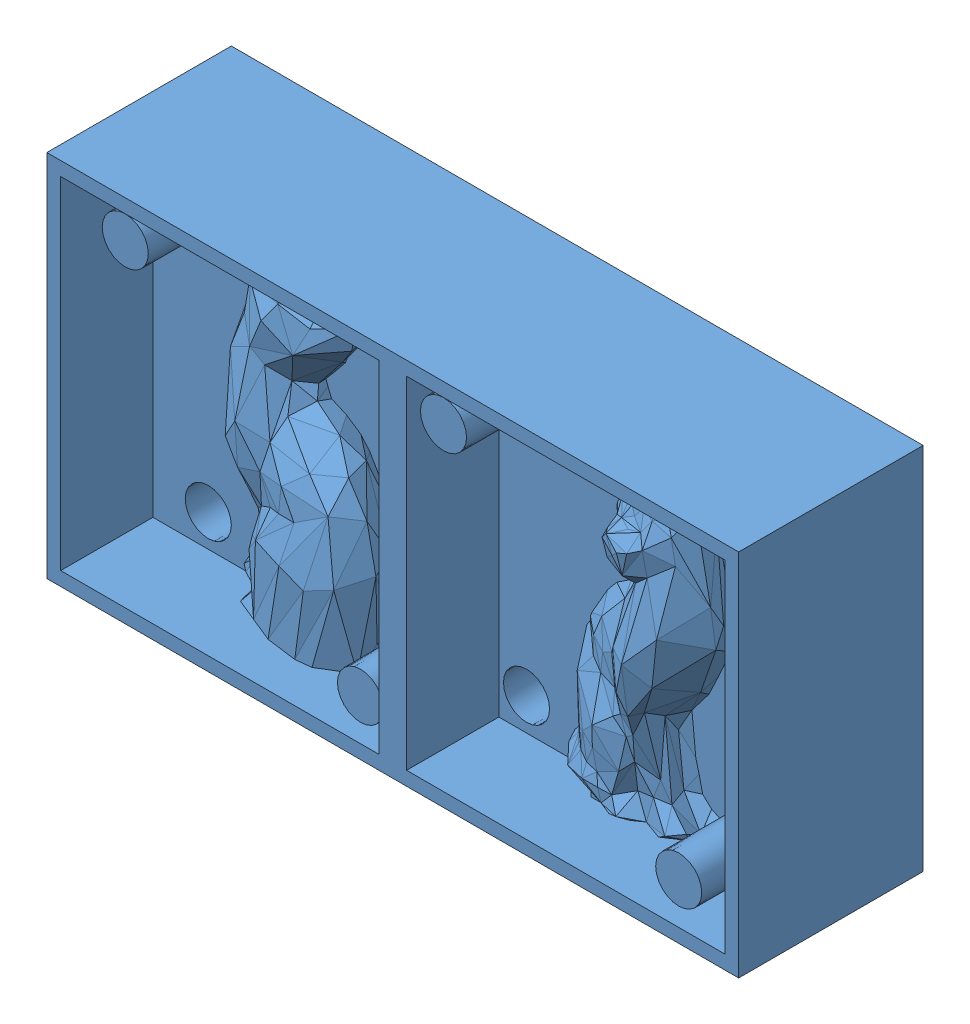
SolidWorks assembly EnsamblajeCat, configuration Predeterminado. Lengths in mm.
Overall size (150 80 40).
3 component instances, 3 part files, 9 mates.
Components (placement in the parent):
- cera-1: cera [Predeterminado] at (3.3673 3.7415 150.05) x (1 0 0) z (0 1 0) size (150 40 80)
- cat back-2: cat back [Predeterminado] at (-33.6496 1.8294 157.829) x (0 0 -1) z (0 1 0) size (14.32 36.7 67.02) (hidden)
- cat front-2: cat front [Predeterminado] at (40.325 -0.9923 158.3372) x (0 0 1) z (0 1 0) size (12.32 35.75 70) (hidden)
Mates (geometry in assembly coordinates):
- Distancia3: distance = 37.5 mm: line of cat front-2 through (40.8673 -30.2585 160.05) axis (0 1 0); line of cera-1 through (78.3673 43.7415 160.05) axis (0 -1 0)
- Distancia5: distance = 37.5 mm: point of assembly; point of cat back-2; moEndPointRef_w of cera-1
- Coincidente13: coincident anti-aligned: plane of cera-1 through (3.3673 3.7415 160.05) normal (0 0 1); plane of cat front-2 through (41.0391 -0.7867 160.05) normal (0 0 -1)
- Coincidente14: coincident anti-aligned: plane of cera-1 through (3.3673 3.7415 160.05) normal (0 0 1); plane of cat back-2 through (-32.5928 -0.7867 160.05) normal (0 0 -1)
- Paralelo1: parallel: line of cera-1 through (78.3673 -36.2585 160.05) axis (-1 0 0); line of cat back-2 through (-20.6615 -30.2585 160.05) axis (-1 0 0)
- Distancia6: distance = 6 mm: line of cat back-2 through (-20.6615 -30.2585 160.05) axis (-1 0 0); line of cera-1 through (78.3673 -36.2585 160.05) axis (-1 0 0)
- Paralelo2: parallel: line of cera-1 through (78.3673 -36.2585 160.05) axis (-1 0 0); line of cat back-2 through (-36.215 -30.2585 160.05) axis (-1 0 0)
- Paralelo3: parallel: line of cera-1 through (78.3673 -36.2585 160.05) axis (-1 0 0); line of cat front-2 through (44.6614 -30.2585 160.05) axis (-1 0 0)
- Distancia7: distance = 6 mm: line of cat front-2 through (44.6614 -30.2585 160.05) axis (-1 0 0); line of cera-1 through (78.3673 -36.2585 160.05) axis (-1 0 0)
